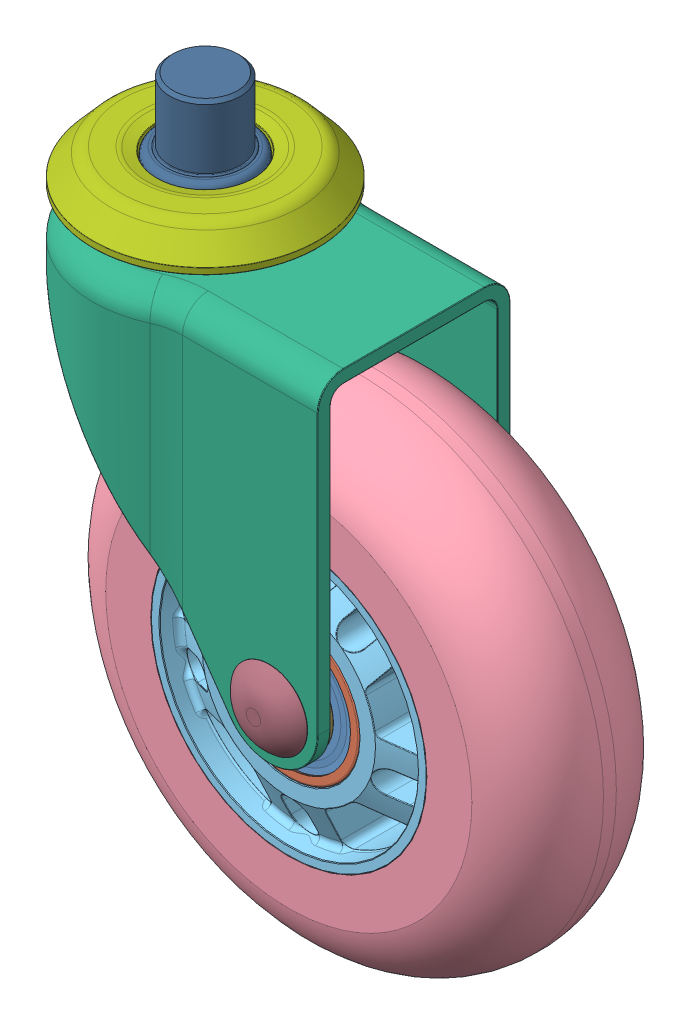
SolidWorks assembly caster-wheel, configuration Default. Lengths in mm.
Overall size (80.5 103.75 35.8).
45 component instances, 13 part files, 0 mates.
Components (placement in the parent):
- OCW_00(2)^caster-wheel-1: OCW_00(2)^caster-wheel [Default] at origin size (80.5 103.75 35.8) (virtual)
  - SKF_608-2Z^OCW_00(2)_caster-wheel-1: SKF_608-2Z^OCW_00(2)_caster-wheel [Default] at (0 0 12) x (0 0 -1) z (-0.332817 0.942991 0) size (7 22 22) (virtual)
    - SKF_608-2Z_PART1^SKF_608-2Z_OCW_00(2)_caster-wheel-1: SKF_608-2Z_PART1^SKF_608-2Z_OCW_00(2)_caster-wheel [Default] at origin size (7 19.2 19.2) (virtual)
    - SKF_608-2Z_PART2^SKF_608-2Z_OCW_00(2)_caster-wheel-1: SKF_608-2Z_PART2^SKF_608-2Z_OCW_00(2)_caster-wheel [Default] at origin size (7 22 22) (virtual)
    - SKF_608-2Z_PART3^SKF_608-2Z_OCW_00(2)_caster-wheel-1: SKF_608-2Z_PART3^SKF_608-2Z_OCW_00(2)_caster-wheel [Default] at origin size (3.97 3.97 3.97) (virtual)
    - SKF_608-2Z_PART3^SKF_608-2Z_OCW_00(2)_caster-wheel-2: SKF_608-2Z_PART3^SKF_608-2Z_OCW_00(2)_caster-wheel [Default] x (1 0 0) z (0 0.781831 0.62349) size (3.97 3.97 3.97) (virtual)
    - SKF_608-2Z_PART3^SKF_608-2Z_OCW_00(2)_caster-wheel-3: SKF_608-2Z_PART3^SKF_608-2Z_OCW_00(2)_caster-wheel [Default] x (1 0 0) z (0 0.974928 -0.222521) size (3.97 3.97 3.97) (virtual)
    - SKF_608-2Z_PART3^SKF_608-2Z_OCW_00(2)_caster-wheel-4: SKF_608-2Z_PART3^SKF_608-2Z_OCW_00(2)_caster-wheel [Default] x (1 0 0) z (0 0.433884 -0.900969) size (3.97 3.97 3.97) (virtual)
    - SKF_608-2Z_PART3^SKF_608-2Z_OCW_00(2)_caster-wheel-5: SKF_608-2Z_PART3^SKF_608-2Z_OCW_00(2)_caster-wheel [Default] x (1 0 0) z (0 -0.433884 -0.900969) size (3.97 3.97 3.97) (virtual)
    - SKF_608-2Z_PART3^SKF_608-2Z_OCW_00(2)_caster-wheel-6: SKF_608-2Z_PART3^SKF_608-2Z_OCW_00(2)_caster-wheel [Default] x (1 0 0) z (0 -0.974928 -0.222521) size (3.97 3.97 3.97) (virtual)
    - SKF_608-2Z_PART3^SKF_608-2Z_OCW_00(2)_caster-wheel-7: SKF_608-2Z_PART3^SKF_608-2Z_OCW_00(2)_caster-wheel [Default] x (1 0 0) z (0 -0.781831 0.62349) size (3.97 3.97 3.97) (virtual)
  - SKF_608-2Z^OCW_00(2)_caster-wheel-2: SKF_608-2Z^OCW_00(2)_caster-wheel [Default] at (0 0 -5) x (0 0 -1) z (-0.040558 0.999177 0) size (7 22 22) (virtual)
    - SKF_608-2Z_PART1^SKF_608-2Z_OCW_00(2)_caster-wheel-1: SKF_608-2Z_PART1^SKF_608-2Z_OCW_00(2)_caster-wheel [Default] at origin size (7 19.2 19.2) (virtual)
    - SKF_608-2Z_PART2^SKF_608-2Z_OCW_00(2)_caster-wheel-1: SKF_608-2Z_PART2^SKF_608-2Z_OCW_00(2)_caster-wheel [Default] at origin size (7 22 22) (virtual)
    - SKF_608-2Z_PART3^SKF_608-2Z_OCW_00(2)_caster-wheel-1: SKF_608-2Z_PART3^SKF_608-2Z_OCW_00(2)_caster-wheel [Default] at origin size (3.97 3.97 3.97) (virtual)
    - SKF_608-2Z_PART3^SKF_608-2Z_OCW_00(2)_caster-wheel-2: SKF_608-2Z_PART3^SKF_608-2Z_OCW_00(2)_caster-wheel [Default] x (1 0 0) z (0 0.781831 0.62349) size (3.97 3.97 3.97) (virtual)
    - SKF_608-2Z_PART3^SKF_608-2Z_OCW_00(2)_caster-wheel-3: SKF_608-2Z_PART3^SKF_608-2Z_OCW_00(2)_caster-wheel [Default] x (1 0 0) z (0 0.974928 -0.222521) size (3.97 3.97 3.97) (virtual)
    - SKF_608-2Z_PART3^SKF_608-2Z_OCW_00(2)_caster-wheel-4: SKF_608-2Z_PART3^SKF_608-2Z_OCW_00(2)_caster-wheel [Default] x (1 0 0) z (0 0.433884 -0.900969) size (3.97 3.97 3.97) (virtual)
    - SKF_608-2Z_PART3^SKF_608-2Z_OCW_00(2)_caster-wheel-5: SKF_608-2Z_PART3^SKF_608-2Z_OCW_00(2)_caster-wheel [Default] x (1 0 0) z (0 -0.433884 -0.900969) size (3.97 3.97 3.97) (virtual)
    - SKF_608-2Z_PART3^SKF_608-2Z_OCW_00(2)_caster-wheel-6: SKF_608-2Z_PART3^SKF_608-2Z_OCW_00(2)_caster-wheel [Default] x (1 0 0) z (0 -0.974928 -0.222521) size (3.97 3.97 3.97) (virtual)
    - SKF_608-2Z_PART3^SKF_608-2Z_OCW_00(2)_caster-wheel-7: SKF_608-2Z_PART3^SKF_608-2Z_OCW_00(2)_caster-wheel [Default] x (1 0 0) z (0 -0.781831 0.62349) size (3.97 3.97 3.97) (virtual)
  - OCW_01^OCW_00(2)_caster-wheel-1: OCW_01^OCW_00(2)_caster-wheel [Default] x (-1 0 0) z (0 0 1) size (76 76 24) (virtual)
  - OCW_02^OCW_00(2)_caster-wheel-1: OCW_02^OCW_00(2)_caster-wheel [Default] x (-1 0 0) z (0 0 1) size (59 59 24.01) (virtual)
  - OCW_03^OCW_00(2)_caster-wheel-1: OCW_03^OCW_00(2)_caster-wheel [Default] at (-17.5 20 0) size (50 55 35.8) (virtual)
  - OCW_05^OCW_00(2)_caster-wheel-1: OCW_05^OCW_00(2)_caster-wheel [Default] at (-25 50.75 0) size (35 5 35) (virtual)
  - OCW_04^OCW_00(2)_caster-wheel-1: OCW_04^OCW_00(2)_caster-wheel [Default] at (-13 50.75 0) x (0.335189 -0.942151 0) z (0.942151 0.335189 0) size (5 5 5) (virtual)
  - OCW_04^OCW_00(2)_caster-wheel-2: OCW_04^OCW_00(2)_caster-wheel [Default] at (-14.1884 50.75 -5.2066) x (0.301995 -0.942151 -0.145433) z (0.848849 0.335189 -0.408784) size (5 5 5) (virtual)
  - OCW_04^OCW_00(2)_caster-wheel-3: OCW_04^OCW_00(2)_caster-wheel [Default] at (-17.5181 50.75 -9.382) x (0.208987 -0.942151 -0.262061) z (0.587422 0.335189 -0.736603) size (5 5 5) (virtual)
  - OCW_04^OCW_00(2)_caster-wheel-4: OCW_04^OCW_00(2)_caster-wheel [Default] at (-22.3297 50.75 -11.6991) x (0.074587 -0.942151 -0.326785) z (0.209648 0.335189 -0.918529) size (5 5 5) (virtual)
  - OCW_04^OCW_00(2)_caster-wheel-5: OCW_04^OCW_00(2)_caster-wheel [Default] at (-27.6703 50.75 -11.6991) x (-0.074587 -0.942151 -0.326785) z (-0.209648 0.335189 -0.918529) size (5 5 5) (virtual)
  - OCW_04^OCW_00(2)_caster-wheel-6: OCW_04^OCW_00(2)_caster-wheel [Default] at (-32.4819 50.75 -9.382) x (-0.208987 -0.942151 -0.262061) z (-0.587422 0.335189 -0.736603) size (5 5 5) (virtual)
  - OCW_04^OCW_00(2)_caster-wheel-7: OCW_04^OCW_00(2)_caster-wheel [Default] at (-35.8116 50.75 -5.2066) x (-0.301995 -0.942151 -0.145433) z (-0.848849 0.335189 -0.408784) size (5 5 5) (virtual)
  - OCW_04^OCW_00(2)_caster-wheel-8: OCW_04^OCW_00(2)_caster-wheel [Default] at (-37 50.75 0) x (-0.335189 -0.942151 0) z (-0.942151 0.335189 0) size (5 5 5) (virtual)
  - OCW_04^OCW_00(2)_caster-wheel-9: OCW_04^OCW_00(2)_caster-wheel [Default] at (-35.8116 50.75 5.2066) x (-0.301995 -0.942151 0.145433) z (-0.848849 0.335189 0.408784) size (5 5 5) (virtual)
  - OCW_04^OCW_00(2)_caster-wheel-10: OCW_04^OCW_00(2)_caster-wheel [Default] at (-32.4819 50.75 9.382) x (-0.208987 -0.942151 0.262061) z (-0.587422 0.335189 0.736603) size (5 5 5) (virtual)
  - OCW_04^OCW_00(2)_caster-wheel-11: OCW_04^OCW_00(2)_caster-wheel [Default] at (-27.6703 50.75 11.6991) x (-0.074587 -0.942151 0.326785) z (-0.209648 0.335189 0.918529) size (5 5 5) (virtual)
  - OCW_04^OCW_00(2)_caster-wheel-12: OCW_04^OCW_00(2)_caster-wheel [Default] at (-22.3297 50.75 11.6991) x (0.074587 -0.942151 0.326785) z (0.209648 0.335189 0.918529) size (5 5 5) (virtual)
  - OCW_04^OCW_00(2)_caster-wheel-13: OCW_04^OCW_00(2)_caster-wheel [Default] at (-17.5181 50.75 9.382) x (0.208987 -0.942151 0.262061) z (0.587422 0.335189 0.736603) size (5 5 5) (virtual)
  - OCW_04^OCW_00(2)_caster-wheel-14: OCW_04^OCW_00(2)_caster-wheel [Default] at (-14.1884 50.75 5.2066) x (0.301995 -0.942151 0.145433) z (0.848849 0.335189 0.408784) size (5 5 5) (virtual)
  - OCW_06^OCW_00(2)_caster-wheel-1: OCW_06^OCW_00(2)_caster-wheel [Default] at (-25 47.5 0) size (24 3.25 24) (virtual)
  - OCW_07^OCW_00(2)_caster-wheel-1: OCW_07^OCW_00(2)_caster-wheel [Default] at (-25 77.95 0) size (21.02 22.8 20.41) (virtual)
  - OCW_08^OCW_00(2)_caster-wheel-1: OCW_08^OCW_00(2)_caster-wheel [Default] at (-25 45.5 0) size (24 0.99 24) (virtual)
  - OCW_10^OCW_00(2)_caster-wheel-1: OCW_10^OCW_00(2)_caster-wheel [Default] at (0 0 12.5) size (14 14 1) (virtual)
  - OCW_10^OCW_00(2)_caster-wheel-2: OCW_10^OCW_00(2)_caster-wheel [Default] at (0 0 -12.5) size (14 14 1) (virtual)
  - OCW_11^OCW_00(2)_caster-wheel-1: OCW_11^OCW_00(2)_caster-wheel [Default] at origin size (11.9 11.9 35) (virtual)
